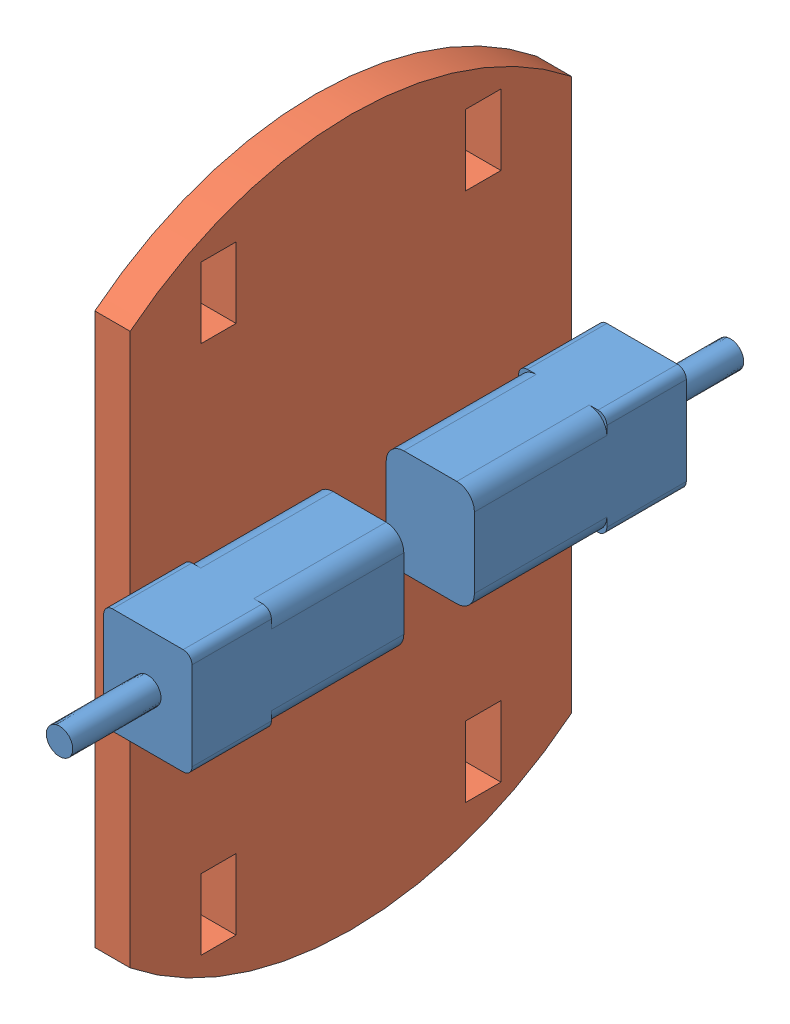
SolidWorks assembly TestBase, configuration Default. Lengths in mm.
Overall size (14 80 76).
3 component instances, 2 part files, 6 mates.
Components (placement in the parent):
- Motor2-1: Motor2 [Default] at (3.0306 11.5113 11.7147) size (10 12 34)
- Base-1: Base [Default] at (-0.9694 17.5113 7.7147) x (0 0 -1) z (0 -1 0) size (50 4 80)
- Motor2-2: Motor2 [Default] at (3.0306 23.5113 3.7147) x (1 0 0) z (0 0 -1) size (10 12 34)
Mates (geometry in assembly coordinates):
- Distance1: distance = 3 mm: plane of Motor2-1 through (4.0306 12.5113 35.7147) normal (0 0 1); plane of Base-1 through (3.0306 17.5113 32.7147) normal (0 0 1)
- Distance2: distance = 3 mm: plane of Motor2-2 through (4.0306 22.5113 -20.2853) normal (0 0 -1); plane of Base-1 through (3.0306 17.5113 -17.2853) normal (0 0 -1)
- Coincident3: coincident: plane of Base-1 through (3.0306 17.5113 5.7147) normal (1 0 0); plane of Motor2-2 through (3.0306 21.5113 -13.2853) normal (-1 0 0)
- Coincident4: coincident: plane of Motor2-1 through (3.0306 13.5113 26.7147) normal (-1 0 0); plane of Base-1 through (3.0306 17.5113 5.7147) normal (1 0 0)
- Width1: width: plane of Base-1 through (3.0306 -8.4887 5.7147) normal (0 -1 0); plane of Motor2-2 through (3.0306 43.5113 5.7147) normal (0 1 0); plane of Base-1 through (5.0306 23.5113 -13.2853) normal (0 1 0); plane of Motor2-2 through (5.0306 11.5113 -13.2853) normal (0 -1 0)
- Coincident5: coincident: plane of Motor2-1 through (5.0306 23.5113 26.7147) normal (0 1 0); plane of Motor2-2 through (5.0306 23.5113 -13.2853) normal (0 1 0)
